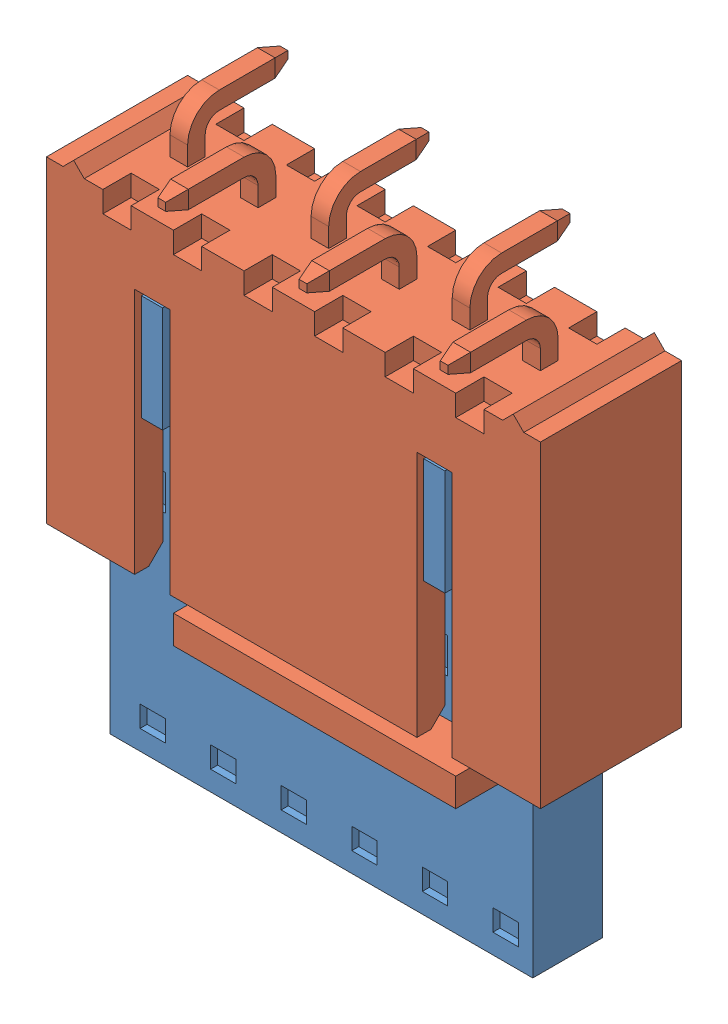
SolidWorks assembly Assem1, configuration Default. Lengths in mm.
Overall size (17.78 19.79 7.53).
2 component instances, 2 part files, 0 mates.
Components (placement in the parent):
- 050579406-1: 050579406 [Default] at (-9.4207 -6.0521 -4.9507) size (15.21 15.24 6.45)
- Part5-2: Part5 [Default] at (-9.3139 -1.4302 -5.1196) x (-1 0 0) z (0 -1 0) size (17.78 7.53 14.28)
